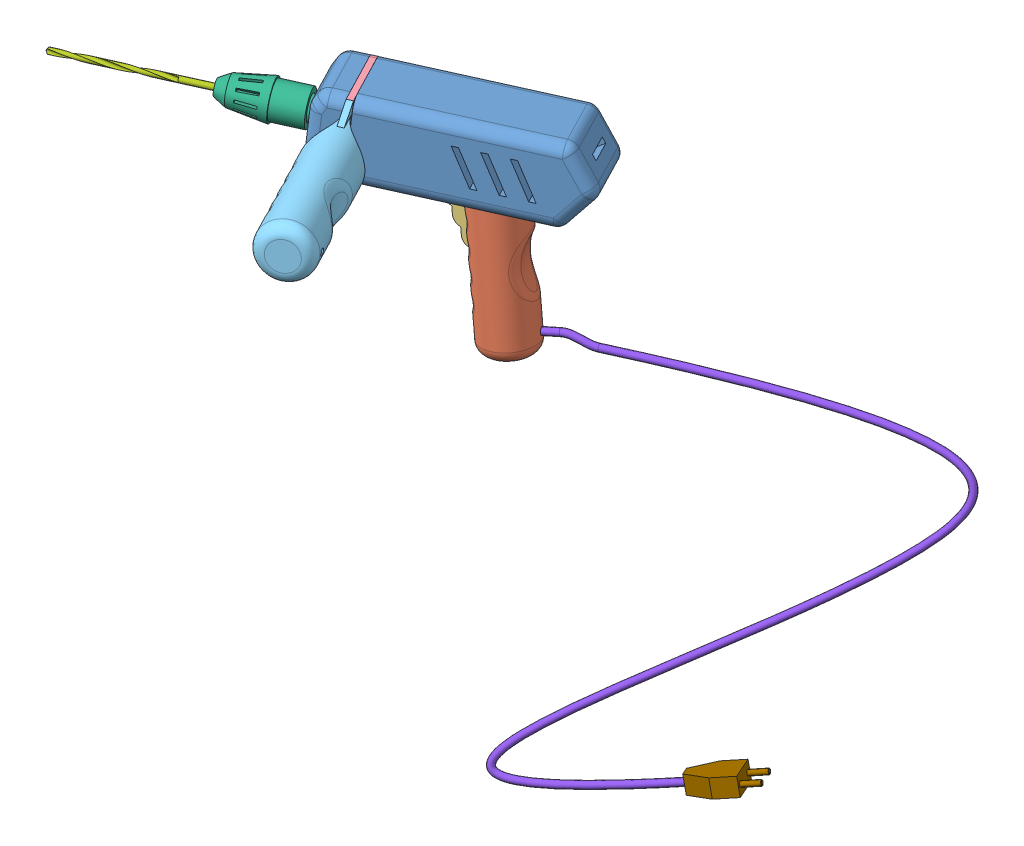
SolidWorks assembly PowerDrillL, configuration Default. Lengths in mm.
Overall size (631.22 489.96 385.82).
9 component instances, 9 part files, 18 mates.
Components (placement in the parent):
- body-2: body [Default] at (72.9871 127.7914 136.1233) x (0.865483 -0.072857 -0.495613) z (0.500931 0.120407 0.857071) size (197.69 64.52 70)
- handle-2: handle [Default] at (119.1866 101.9555 154.307) x (0.852815 0.10017 -0.512517) z (0.147563 -0.987658 0.052507) size (45.68 45 121.93)
- triger-1: triger [Default] at (107.8799 58.4933 166.3019) x (-0.500931 -0.120407 -0.857071) z (0.852815 0.10017 -0.512517) size (15 44.12 15)
- support-1: support [Default] at (20.6215 101.9864 178.3685) x (0.865483 -0.072857 -0.495613) z (0.00704 0.991038 -0.133393) size (5 70 64.5)
- handle - support-1: handle - support [Default] at (72.1432 145.483 262.4771) x (0.865483 -0.072857 -0.495613) z (0.50089 0.11196 0.858239) size (45.68 64.5 162.73)
- chalck-1: chalck [Default] at (20.762 131.7872 199.9852) x (0.865483 -0.072857 -0.495613) z (0.322103 -0.676786 0.661975) size (88 32.58 32.58)
- drillbit-1: drillbit [Default] at (-148.4766 151.9997 302.9979) x (-0.099286 0.944791 -0.312269) z (-0.491001 -0.319471 -0.810467) size (9.13 120.25 9.17)
- wire-2: wire [Default] at (134.5331 -0.7609 159.7677) x (-0.462848 -0.309487 -0.830656) z (-0.852815 -0.10017 0.512517) size (6 313.64 335.27)
- plug-1: plug [Default] at (331.9313 -259.418 139.5276) x (-0.49471 -0.214781 -0.842099) z (0.292288 -0.953652 0.071522) size (30 54.34 15)
Mates (geometry in assembly coordinates):
- Concentric3: concentric anti-aligned: cylinder of body-2 through (116.0675 122.8317 153.1972) axis (0.147563 -0.987658 0.052507) radius 7.3861; cylinder of handle-2 through (122.5805 79.2394 155.5147) axis (-0.147563 0.987658 -0.052507) radius 7.5
- Coincident1: coincident anti-aligned: plane of body-2 through (180.6752 98.5001 158.9715) normal (-0.002768 -0.990047 0.140707); plane of handle-2 through (137.6144 92.8772 118.5597) normal (0.002768 0.990047 -0.140707)
- Parallel2: parallel aligned: plane of body-2 through (72.9871 127.7914 136.1233) normal (-0.500931 -0.120407 -0.857071); plane of triger-1 through (104.1229 57.5902 159.8738) normal (-0.500931 -0.120407 -0.857071)
- Coincident4: coincident anti-aligned: plane of body-2 through (180.6752 98.5001 158.9715) normal (-0.002768 -0.990047 0.140707); plane of triger-1 through (92.6905 102.9804 188.7647) normal (0.002768 0.990047 -0.140707)
- Width1: width aligned: plane of body-2 through (72.9871 127.7914 136.1233) normal (-0.500931 -0.120407 -0.857071); plane of body-2 through (108.0523 136.2199 196.1183) normal (0.500931 0.120407 0.857071); plane of triger-1 through (104.1229 57.5902 159.8738) normal (-0.500931 -0.120407 -0.857071); plane of triger-1 through (111.6369 59.3963 172.7299) normal (0.500931 0.120407 0.857071)
- Distance2: distance = 90 mm: line of triger-1 through (84.8207 99.6598 165.2452) axis (0.500931 0.120407 0.857071); plane of body-2 through (28.2512 123.612 244.5309) normal (-0.865483 0.072857 0.495613)
- Coincident13: coincident anti-aligned: line of support-1 through (50.171 173.1477 225.0846) axis (-0.00704 -0.991038 0.133393); line of handle - support-1 through (50.1014 163.347 226.4038) axis (0.00704 0.991038 -0.133393)
- Coincident14: coincident aligned: line of support-1 through (50.171 173.1477 225.0846) axis (0.865483 -0.072857 -0.495613); line of handle - support-1 through (50.171 173.1477 225.0846) axis (0.865483 -0.072857 -0.495613)
- Concentric6: concentric aligned: cylinder of body-2 through (36.7367 136.4083 196.9368) axis (-0.865483 0.072857 0.495613) radius 10; cylinder of chalck-1 through (-27.309 141.7997 233.6121) axis (-0.865483 0.072857 0.495613) radius 10
- Distance3: distance = 5 mm anti-aligned: plane of chalck-1 through (10.2813 146.284 219.906) normal (0.865483 -0.072857 -0.495613); plane of body-2 through (28.2512 123.612 244.5309) normal (-0.865483 0.072857 0.495613)
- Concentric7: concentric anti-aligned: cylinder of chalck-1 through (-47.2151 143.4755 245.0112) axis (0.865483 -0.072857 -0.495613) radius 2.5; cylinder of drillbit-1 through (-44.6187 143.2569 243.5244) axis (-0.865483 0.072857 0.495613) radius 2.5
- Distance5: distance = 20 mm anti-aligned: plane of chalck-1 through (-25.314 145.6091 236.536) normal (-0.865483 0.072857 0.495613); plane of drillbit-1 through (-44.6187 143.2569 243.5244) normal (0.865483 -0.072857 -0.495613)
- Concentric11: concentric anti-aligned: cylinder of handle-2 through (228.3427 10.2578 103.3909) axis (-0.852815 -0.10017 0.512517) radius 3; cylinder of wire-2 through (134.5331 -0.7609 159.7677) axis (0.852815 0.10017 -0.512517) radius 3
- Coincident25: coincident anti-aligned: circle of handle-2; circle of wire-2
- Distance7: distance = 0 mm anti-aligned: plane of support-1 through (19.4361 164.9462 162.5298) normal (0.865483 -0.072857 -0.495613); plane of body-2 through (36.7367 136.4083 196.9368) normal (-0.865483 0.072857 0.495613)
- Concentric14: concentric anti-aligned: cylinder of body-2 through (32.4093 136.7726 199.4149) axis (0.865483 -0.072857 -0.495613) radius 21.9509; cylinder of support-1 through (41.0641 136.044 194.4588) axis (-0.865483 0.072857 0.495613) radius 21.9509
- Coincident26: coincident aligned: circle of wire-2; circle of plug-1
- Lock1: lock: unknown of wire-2; unknown of plug-1
